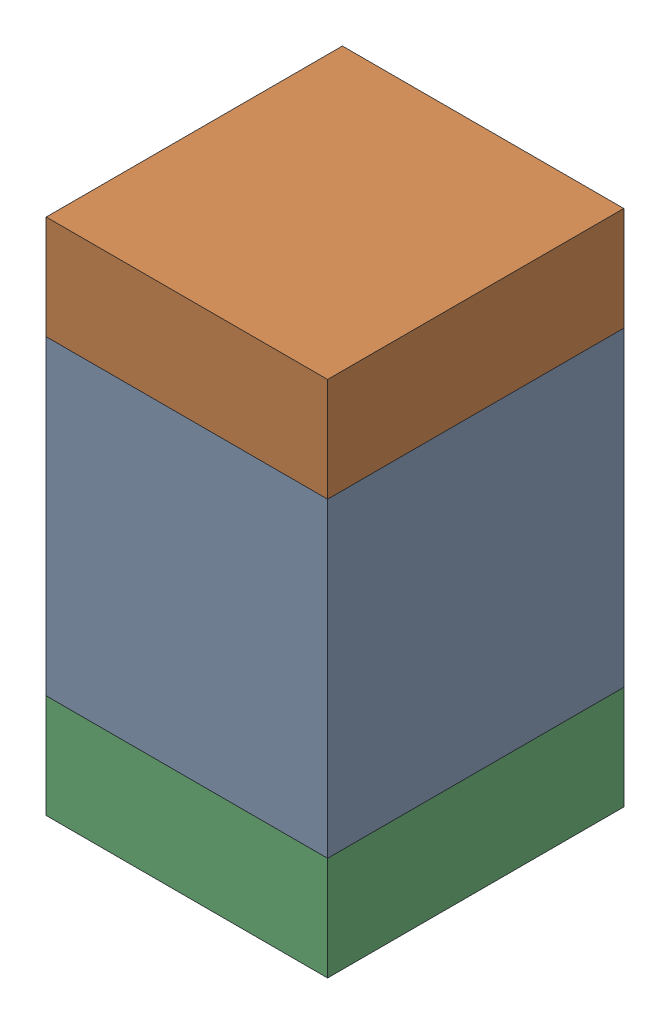
SolidWorks assembly C318_1PCB, configuration Default. Lengths in mm.
Overall size (0.95 1.75 1).
6 component instances, 2 part files, 0 mates.
Components (placement in the parent):
- 761616384-1: 761616384 [Default] at (131.6 105.6 -2.6638) size (0.95 1.05 1)
  - Extruded_5-1: Extruded_5 [Default] at origin size (0.95 1.05 1)
- 761616520-1: 761616520 [Default] at (131.6 106.3 -2.6638) size (0.95 0.35 1)
  - Extruded_6-1: Extruded_6 [Default] at origin size (0.95 0.35 1)
- 761616520-2: 761616520 [Default] at (131.6 104.9 -2.6638) size (0.95 0.35 1)
  - Extruded_6-1: Extruded_6 [Default] at origin size (0.95 0.35 1)
